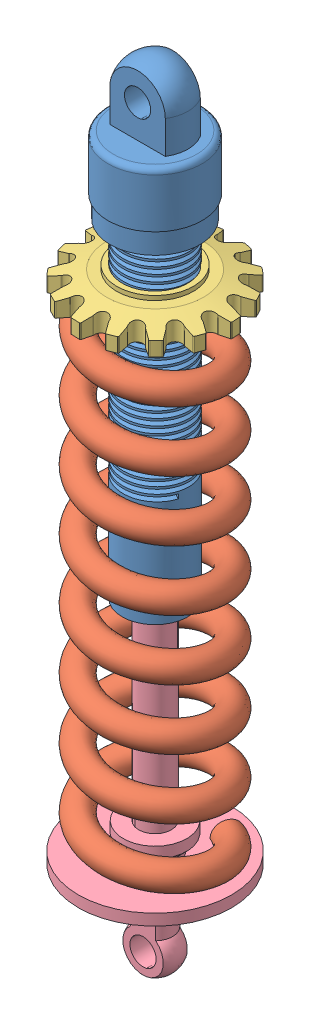
SolidWorks assembly Shock Absorber, configuration Default. Lengths in mm.
Overall size (98.64 363 98.64).
4 component instances, 4 part files, 7 mates.
Components (placement in the parent):
- BaseRosca-2: BaseRosca [Predeterminado] at origin size (43 215 43)
- Spring-2: Spring [Predeterminado] at (0 -97.5 0) x (0.408238 0 -0.912876) z (0.912876 0 0.408238) size (63.95 244 65.19)
- Tuerca-1: Tuerca [Predeterminado] at (0 12.5 0) x (0.700607 0 -0.713548) z (0.713548 0 0.700607) size (69.91 13.31 69.59)
- Inferior-1: Inferior [Predeterminado] at (0 -175.5 0) x (0 0 -1) z (-1 0 0) size (70 160 70)
Mates (geometry in assembly coordinates):
- Concéntrica1: concentric aligned: cylinder of BaseRosca-2 through (0 57.3408 0) axis (0 1 0) radius 15; circle of Spring-2
- Tornillo1: screw = 1 anti-aligned: cylinder of BaseRosca-2 through (0 57.3408 0) axis (0 1 0) radius 15; cylinder of Tuerca-1 through (0 22.5 0) axis (0 -1 0) radius 14
- Coincidente2: coincident anti-aligned: plane of Spring-2 through (0 12.5 0) normal (0 1 0); plane of Tuerca-1 through (0 12.5 0) normal (0 -1 0)
- Distancia1: distance = 20 mm anti-aligned: plane of Tuerca-1 through (0 22.5 0) normal (0 1 0); plane of BaseRosca-2 through (-20.5 42.5 0) normal (0 -1 0)
- Concéntrica4: concentric anti-aligned: cylinder of BaseRosca-2 through (0 -27.5 0) axis (0 -1 0) radius 7.5; cylinder of Inferior-1 through (0 -95.5 0) axis (0 1 0) radius 7.5
- Coincidente4: coincident anti-aligned: plane of Spring-2 through (0 -207.5 0) normal (0 -1 0); plane of Inferior-1 through (0 -207.5 10) normal (0 1 0)
- Paralelo1: parallel aligned: plane of BaseRosca-2 through (-20 77.5 8) normal (0 0 1); plane of Inferior-1 through (40 -175.5 5.5) normal (0 0 1)
